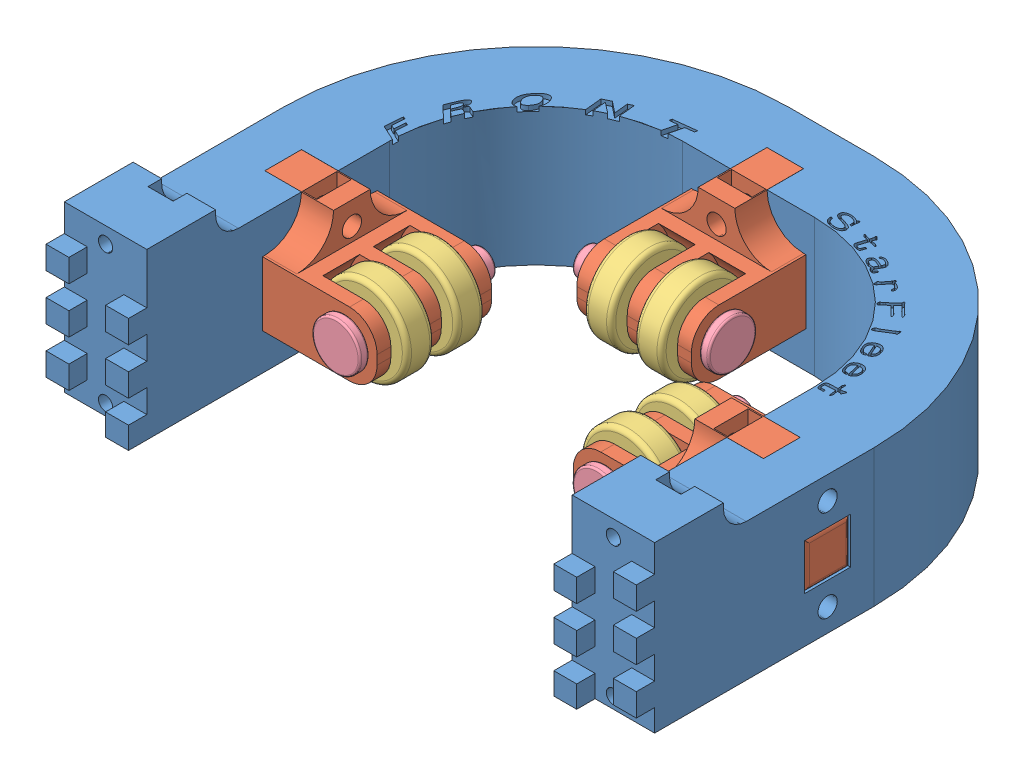
SolidWorks assembly 上定心组装体, configuration 默认. Lengths in mm.
Overall size (128.8 36 106.92).
13 component instances, 4 part files, 15 mates.
Components (placement in the parent):
- 上定心母打印件-1: 上定心母打印件 [默认] at (-118.4802 9.7587 135.9389) size (128.8 36 106.92)
- 上定心子打印件-1: 上定心子打印件 [默认] at (-137.7341 9.7587 2.21) x (0 0 1) z (0 1 0) size (25 43 30)
- 上定心子打印件-2: 上定心子打印件 [默认] at (-85.8341 9.7587 -25.46) x (-1 0 0) z (0 1 0) size (25 43 30)
- 上定心子打印件-3: 上定心子打印件 [默认] at (-58.9341 9.7587 27.21) x (0 0 -1) z (0 1 0) size (25 43 30)
- 直径6厚度6外径19大轴承-1: 直径6厚度6外径19大轴承 [默认] at (-69.9341 9.7587 17.21) x (0 0 1) z (-0.924225 0.381849 0) size (6 19 19)
- 直径6厚度6外径19大轴承-2: 直径6厚度6外径19大轴承 [默认] at (-106.8341 9.7587 -14.46) size (6 19 19)
- 直径6厚度6外径19大轴承-3: 直径6厚度6外径19大轴承 [默认] at (-126.7341 9.7587 23.21) x (0 0 -1) z (0.923728 0.383049 0) size (6 19 19)
- 直径6厚度6外径19大轴承-4: 直径6厚度6外径19大轴承 [默认] at (-69.9341 9.7587 6.21) x (0 0 1) z (-0.924225 0.381849 0) size (6 19 19)
- 直径6厚度6外径19大轴承-5: 直径6厚度6外径19大轴承 [默认] at (-126.7341 9.7587 12.21) x (0 0 -1) z (1 0 0) size (6 19 19)
- 直径6厚度6外径19大轴承-6: 直径6厚度6外径19大轴承 [默认] at (-95.8341 9.7587 -14.46) size (6 19 19)
- 有效27直径6带槽圆柱销-1: 有效27直径6带槽圆柱销 [默认] at (-126.7341 9.7587 27.21) x (0 0 1) z (-0.923728 -0.383049 0) size (32 10.5 10.5)
- 有效27直径6带槽圆柱销-2: 有效27直径6带槽圆柱销 [默认] at (-85.8341 9.7587 -14.46) size (32 10.5 10.5)
- 有效27直径6带槽圆柱销-3: 有效27直径6带槽圆柱销 [默认] at (-69.9341 9.7587 27.21) x (0 0 1) z (-0.924225 0.381849 0) size (32 10.5 10.5)
Mates (geometry in assembly coordinates):
- 重合1: coincident anti-aligned: circle of 定心大打印件-1; circle of 定心小打印件-1
- 同心1: concentric aligned: cylinder of 定心大打印件-1 through (-644.7341 -0.2413 14.71) axis (1 0 0) radius 2.1; cylinder of 定心小打印件-1 through (-164.0478 -0.2413 14.71) axis (1 0 0) radius 2.1
- 重合2: coincident anti-aligned: circle of 定心小打印件-1; circle of 直径6厚度6外径19大轴承-5
- 重合3: coincident aligned: circle of 定心小打印件-1; circle of 直径6厚度6外径19大轴承-3
- 重合4: coincident anti-aligned: circle of 定心小打印件-2; circle of 直径6厚度6外径19大轴承-6
- 重合5: coincident aligned: circle of 定心小打印件-2; circle of 直径6厚度6外径19大轴承-2
- 重合6: coincident aligned: circle of 定心小打印件-3; circle of 直径6厚度6外径19大轴承-4
- 重合7: coincident anti-aligned: circle of 定心小打印件-3; circle of 直径6厚度6外径19大轴承-1
- 重合8: coincident aligned: circle of 定心小打印件-1; circle of 有效27直径6带槽圆柱销-1
- 重合9: coincident anti-aligned: circle of 定心小打印件-2; circle of 有效27直径6带槽圆柱销-2
- 重合13: coincident anti-aligned: circle of 定心小打印件-3; circle of 有效27直径6带槽圆柱销-3
- 重合14: coincident anti-aligned: circle of 定心大打印件-1; circle of 定心小打印件-2
- 重合15: coincident anti-aligned: circle of 定心大打印件-1; circle of 定心小打印件-2
- 重合17: coincident aligned: circle of 定心大打印件-1; circle of 定心小打印件-3
- 重合18: coincident aligned: circle of 定心大打印件-1; circle of 定心小打印件-3
